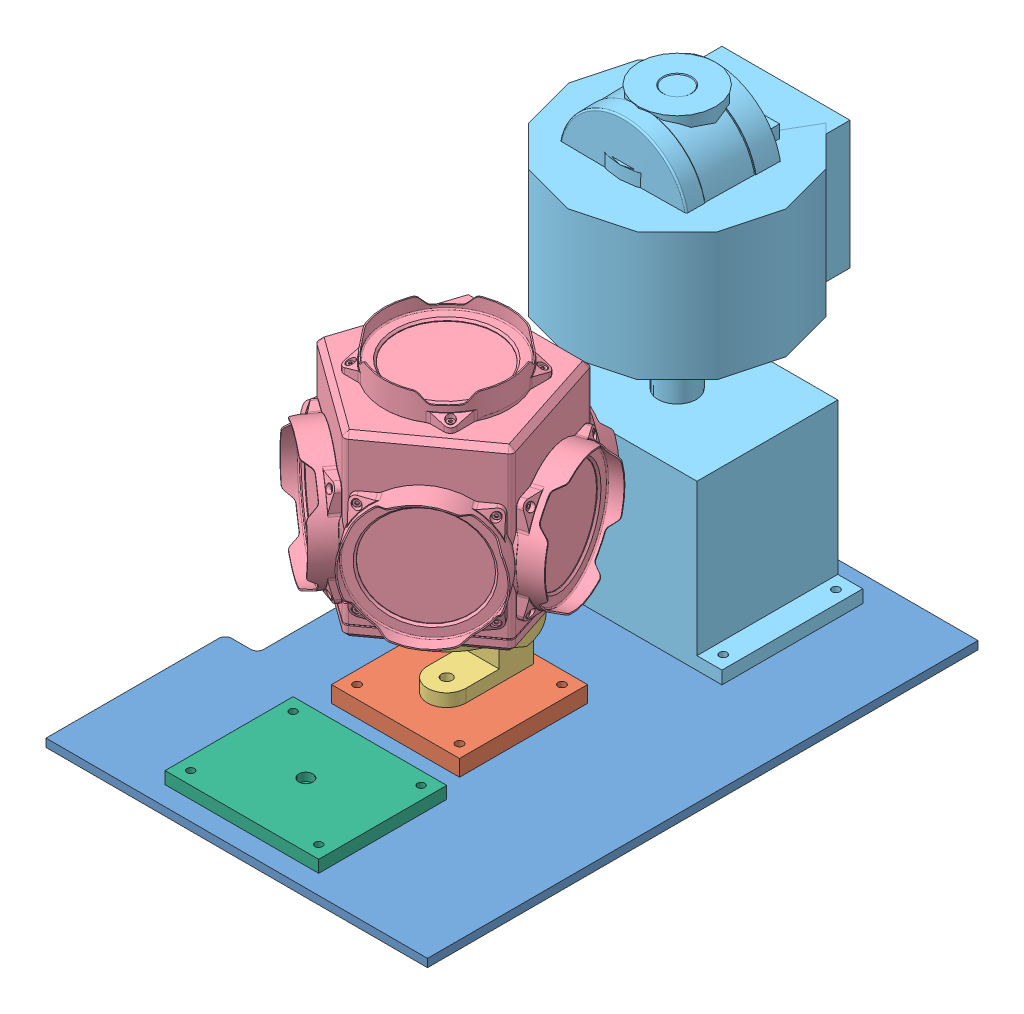
SolidWorks assembly sensor_suite, configuration Default. Lengths in mm.
Overall size (298 339.99 453.62).
7 component instances, 7 part files, 24 mates.
Components (placement in the parent):
- deck_lid-1: deck_lid [Default] at origin size (298 6.35 430)
- Ladybug_mount_plate-1: Ladybug_mount_plate [Default] at (0 6.35 40) size (100 12.7 100)
- OEM_Mount-1: OEM_Mount [Default] at (0 19.05 40) size (110 76.2 102.63)
- LD5-001-R0-1: LD5-001-R0 [Default] at (0 155.75 40) x (-1 0 0) z (0 0 -1) size (192.91 159.78 183.75)
- lidar_rotater-1: lidar_rotater [Default] at (0 6.35 -140) x (0 0 -1) z (1 0 0) size (197.23 333.64 197.23)
- VLP-16-1: VLP-16 [Default] at (0 15.875 150) x (-1 0 0) z (0 0 -1) size (232.88 72.75 103.27)
- Lidar_mount_plate-1: Lidar_mount_plate [Default] at (0 15.875 150) x (1 0 0) z (0 0 -1) size (120 9.53 100)
Mates (geometry in assembly coordinates):
- Coincident1: coincident aligned: plane of deck_lid-1 through (0 0 0) normal (0 0 1); plane of assembly through (0 0 0) normal (0 0 1)
- Coincident2: coincident aligned: plane of deck_lid-1 through (0 0 0) normal (1 0 0); plane of assembly through (0 0 0) normal (1 0 0)
- Coincident3: coincident aligned: plane of deck_lid-1 through (0 0 0) normal (0 1 0); plane of assembly through (0 0 0) normal (0 1 0)
- Coincident4: coincident aligned: plane of deck_lid-1 through (0 6.35 0) normal (0 1 0); plane of OEM_Mount-1 through (0 19.05 40) normal (0 1 0)
- Distance1: distance = 20 mm: line of assembly; line of OEM_Mount-1 through (0 99.06 40) axis (0 -1 0); plane of assembly
- Coincident6: coincident aligned: plane of OEM_Mount-1 through (0 19.05 40) normal (1 0 0); plane of assembly through (0 0 0) normal (1 0 0)
- Coincident7: coincident anti-aligned: plane of OEM_Mount-1 through (0 95.25 40) normal (0 1 0); plane of LD5-001-R0-1 through (0 95.25 116.0182) normal (0 -1 0)
- Coincident8: coincident anti-aligned: line of OEM_Mount-1 through (0 99.06 40) axis (0 -1 0); line of LD5-001-R0-1 through (0 95.25 40) axis (0 1 0)
- Parallel1: parallel anti-aligned: plane of LD5-001-R0-1 through (0 155.75 40) normal (0 0 -1); plane of assembly through (0 0 0) normal (0 0 1)
- Coincident10: coincident anti-aligned: plane of deck_lid-1 through (0 6.35 0) normal (0 1 0); plane of LiDAR_rotater-1 through (0 6.35 -140) normal (0 -1 0)
- Distance2: distance = 140 mm: plane of assembly through (0 0 0) normal (0 0 1); line of LiDAR_rotater-1 through (0 6.35 -140) axis (0 1 0)
- Angle1: planar angle = 1.570796 rad aligned: plane of LiDAR_rotater-1 through (0 6.35 -140) normal (0 0 -1); plane of assembly through (0 0 0) normal (1 0 0)
- Coincident17: coincident anti-aligned: plane of deck_lid-1 through (0 6.35 0) normal (0 1 0); plane of Lidar_mount_plate-1 through (0 6.35 150) normal (0 -1 0)
- Coincident18: coincident anti-aligned: plane of 86-0101 REV B ENVELOPE, VLP-16-1 through (51.6361 15.875 150) normal (0 -1 0); plane of Lidar_mount_plate-1 through (0 15.875 150) normal (0 1 0)
- Coincident22: coincident aligned: plane of Lidar_mount_plate-1 through (0 15.875 150) normal (1 0 0); plane of assembly through (0 0 0) normal (1 0 0)
- Coincident20: coincident anti-aligned: line of 86-0101 REV B ENVELOPE, VLP-16-1 through (0 88.6213 150) axis (0 -1 0); line of Lidar_mount_plate-1 through (0 2.54 150) axis (0 1 0)
- Distance3: distance = 150 mm: line of Lidar_mount_plate-1 through (0 2.54 150) axis (0 1 0); plane of assembly through (0 0 0) normal (0 0 1)
- Angle3: planar angle = 3.141593 rad aligned: plane of Lidar_mount_plate-1 through (0 15.875 150) normal (1 0 0); plane of 86-0101 REV B ENVELOPE, VLP-16-1 through (0 15.875 150) normal (-1 0 0)
- Coincident24: coincident: line of LiDAR_rotater-1 through (0 6.35 -140) axis (0 1 0); plane of assembly through (0 0 0) normal (1 0 0)
- Coincident29: coincident anti-aligned: plane of deck_lid-1 through (0 6.35 0) normal (0 1 0); plane of Ladybug_mount_plate-1 through (0 6.35 40) normal (0 -1 0)
- Coincident30: coincident aligned: plane of Ladybug_mount_plate-1 through (0 6.35 40) normal (1 0 0); plane of assembly through (0 0 0) normal (1 0 0)
- Distance4: distance = 40 mm: plane of assembly through (0 0 0) normal (0 0 1); plane of assembly; plane of Ladybug_mount_plate-1 through (0 6.35 40) normal (0 0 1)
- Coincident33: coincident aligned: line of Ladybug_mount_plate-1 through (0 19.05 40) axis (0 -1 0); line of OEM_Mount-1 through (0 99.06 40) axis (0 -1 0)
- Coincident36: coincident anti-aligned: plane of Ladybug_mount_plate-1 through (0 19.05 40) normal (0 1 0); plane of OEM_Mount-1 through (0 19.05 40) normal (0 -1 0)
